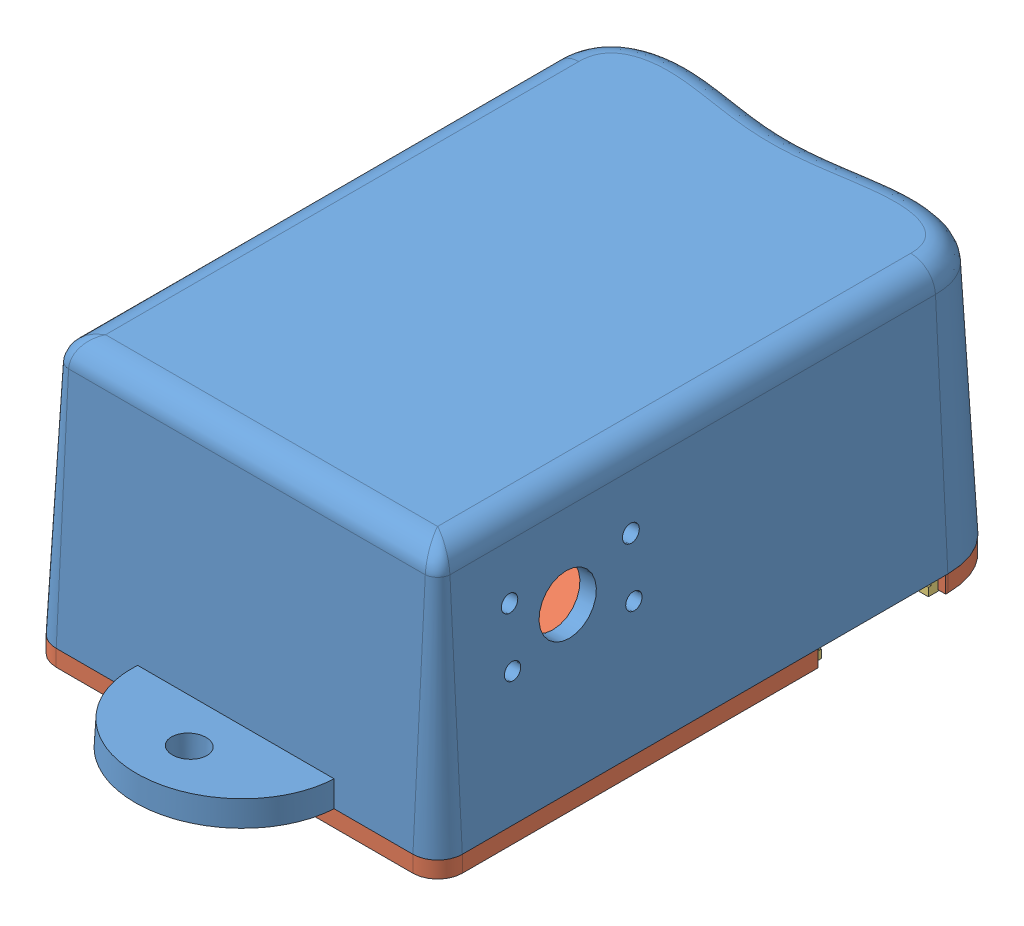
SolidWorks assembly Assem1, configuration Default. Lengths in mm.
Overall size (105.28 67.33 170.71).
3 component instances, 3 part files, 2 mates.
Components (placement in the parent):
- top_part-1: top_part [Default] at (-109.7765 383.1056 1248.2314) size (105.28 64.38 170.71)
- bottom-1: bottom [Default] at (-109.7765 379.1056 1248.2314) size (98.68 19 143.91)
- best_holder-1: best_holder [Default] at (-55.3891 402.7813 1116.8583) x (1 0 0) z (0 -1 0) size (51 64.52 25)
Mates (geometry in assembly coordinates):
- Coincident1: coincident aligned: line of top_part-1 through (-95.6854 383.1056 1239.9984) axis (1 0 0); line of bottom-1 through (-95.6854 383.1056 1239.9984) axis (1 0 0)
- Coincident2: coincident aligned: line of top_part-1 through (-3.0068 383.1056 1116.0059) axis (0 0 1); line of bottom-1 through (-3.0068 383.1056 1116.0059) axis (0 0 1)
